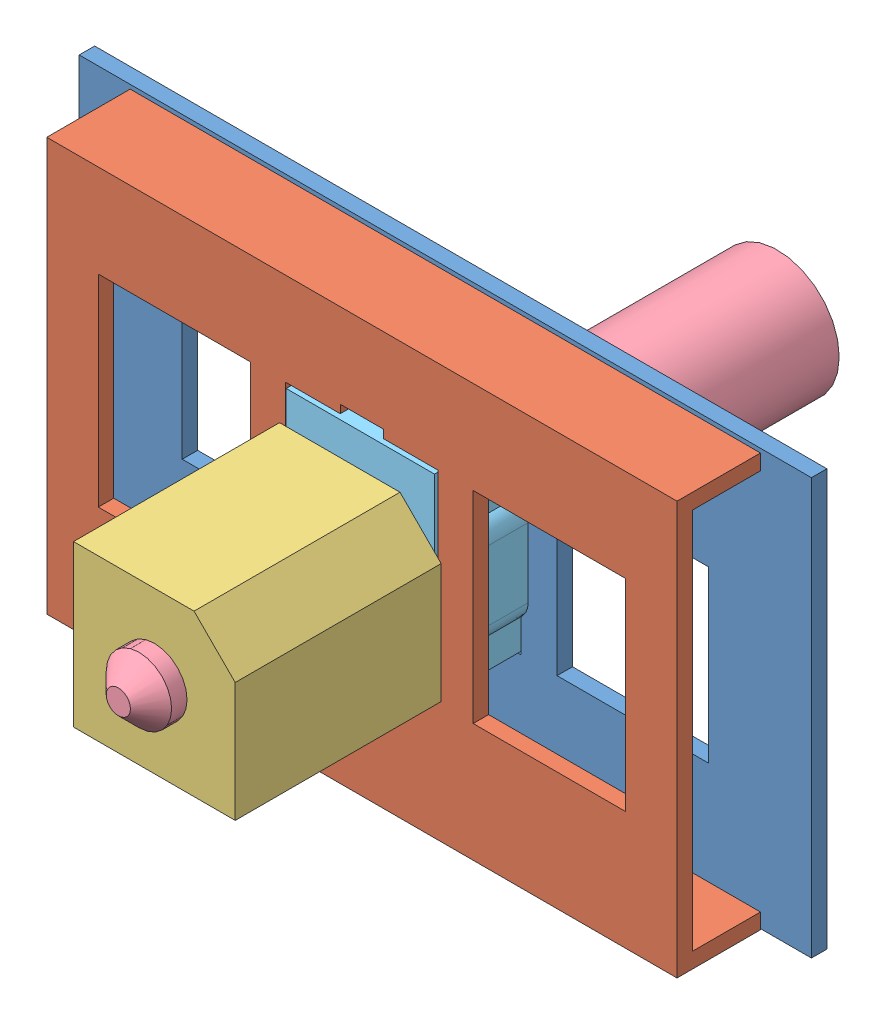
SolidWorks assembly key-proto, configuration Standard. Lengths in mm.
Overall size (71.1 40.5 64).
5 component instances, 5 part files, 12 mates.
Components (placement in the parent):
- Key-Outer-1: Key-Outer [Standard] at (2.0032 -1.5897 54.7028) size (71.1 40.4 1.5)
- key-inner-1: key-inner [Standard] at (-2.9468 -0.1897 62.8028) size (61.2 40.1 8.1)
- 6,35mm-buchse-1: 6,35mm-buchse [Standard] at (-41.5468 10.1103 84.3028) x (-1 0 0) z (0 0 -1) size (15.7 15.6 27.5)
- 6,35mm-Stecker-1: 6,35mm-Stecker [Standard] at (-33.6968 17.9103 56.8028) size (12 12 64)
- keystone-6,35mm-halter-1: keystone-6,35mm-halter [Standard] at (-26.4968 9.8103 54.7028) size (16.4 21.1 9.6)
Mates (geometry in assembly coordinates):
- Deckungsgleich1: coincident anti-aligned: plane of key-inner-1 through (-2.9468 -0.1897 56.2028) normal (0 0 -1); plane of Key-Outer-1 through (2.0032 -1.5897 56.2028) normal (0 0 1)
- Abstand1: distance = 0.05 mm aligned: plane of key-inner-1 through (-40.9468 -0.1897 64.3028) normal (1 0 0); plane of Key-Outer-1 through (-40.8968 26.3103 56.2028) normal (1 0 0)
- Deckungsgleich3: coincident aligned: plane of Key-Outer-1 through (-59.0968 9.8103 56.2028) normal (0 1 0); plane of key-inner-1 through (-2.9468 9.8103 64.3028) normal (0 1 0)
- Parallel1: parallel anti-aligned: plane of key-inner-1 through (-2.9468 -0.1897 64.3028) normal (0 0 1); plane of 6,35mm-buchse-1 through (-41.5468 10.1103 64.3028) normal (0 0 -1)
- Parallel2: parallel aligned: plane of key-inner-1 through (-64.1468 -0.1897 64.3028) normal (-1 0 0); plane of 6,35mm-buchse-1 through (-41.5468 10.1103 64.3028) normal (-1 0 0)
- Konzentrisch1: concentric anti-aligned: cylinder of 6,35mm-buchse-1 through (-33.6968 17.9103 56.8028) axis (0 0 1) radius 3.25; cylinder of 6,35mm-Stecker-1 through (-33.6968 17.9103 87.8028) axis (0 0 -1) radius 3.175
- Deckungsgleich6: coincident anti-aligned: plane of 6,35mm-buchse-1 through (-33.6968 17.9103 56.8028) normal (0 0 -1); plane of 6,35mm-Stecker-1 through (-33.6968 17.9103 56.8028) normal (0 0 1)
- Deckungsgleich7: coincident anti-aligned: plane of Key-Outer-1 through (-40.8968 26.3103 56.2028) normal (1 0 0); plane of keystone-6,35mm-halter-1 through (-40.8968 9.8103 56.2028) normal (-1 0 0)
- Deckungsgleich8: coincident aligned: plane of Key-Outer-1 through (2.0032 -1.5897 54.7028) normal (0 0 -1); plane of keystone-6,35mm-halter-1 through (-26.4968 9.8103 54.7028) normal (0 0 -1)
- Deckungsgleich9: coincident anti-aligned: plane of Key-Outer-1 through (-40.8968 9.8103 56.2028) normal (0 1 0); plane of keystone-6,35mm-halter-1 through (-26.4968 9.8103 56.2028) normal (0 -1 0)
- Konzentrisch2: concentric anti-aligned: cylinder of 6,35mm-Stecker-1 through (-33.6968 17.9103 23.8028) axis (0 0 1) radius 6; cylinder of keystone-6,35mm-halter-1 through (-33.6968 17.9103 56.2028) axis (0 0 -1) radius 6.5
- Deckungsgleich10: coincident anti-aligned: plane of 6,35mm-buchse-1 through (-41.5468 10.1103 64.3028) normal (0 0 -1); plane of keystone-6,35mm-halter-1 through (-26.4968 9.8103 64.3028) normal (0 0 1)
